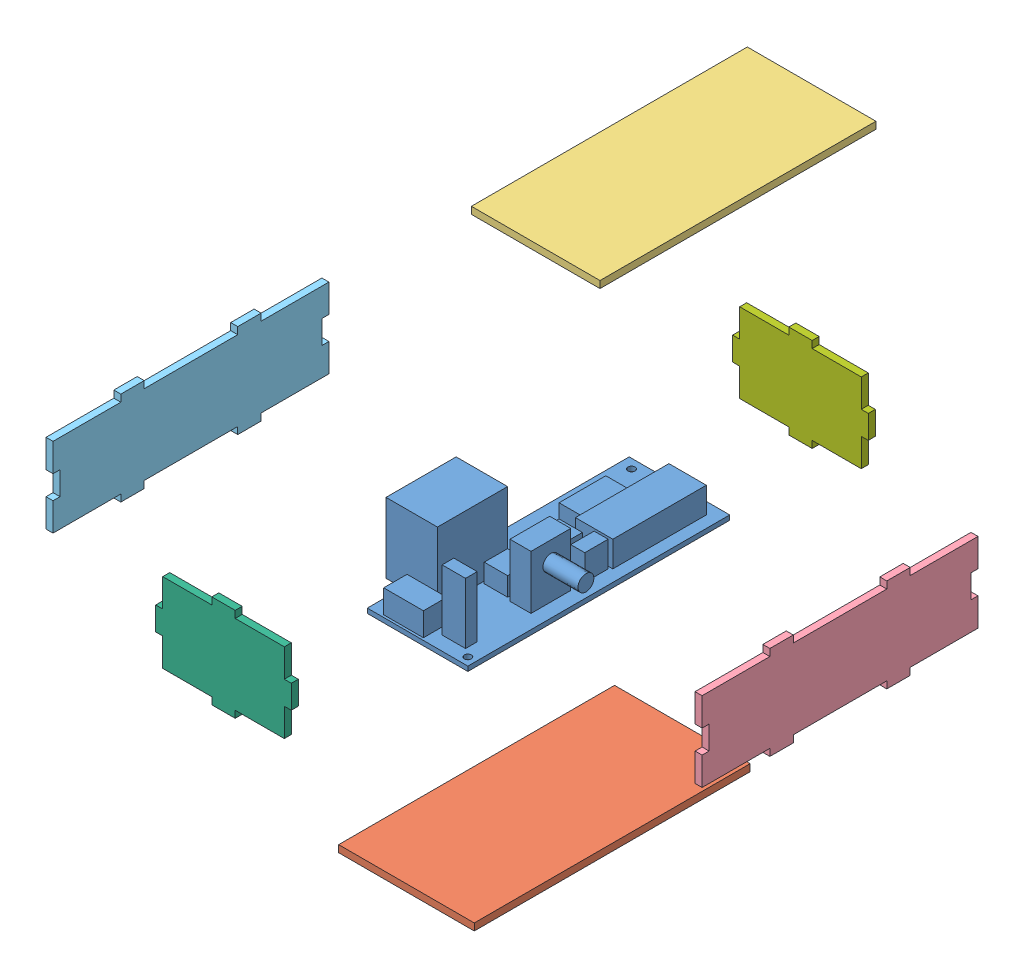
SolidWorks assembly Assem1, configuration Default. Lengths in mm.
Overall size (190.05 127.77 267.42).
7 component instances, 7 part files, 0 mates.
Components (placement in the parent):
- Board-1: Board [Default] at (38.8628 52.2316 80.3483) size (59 32 112)
- Part1-1: Part1 [Default] at (95.8183 19.1955 139.0641) size (58 3 118)
- Part1 - Copy-1: Part1 - Copy [Default] at (6.8607 139.7799 -5.1669) size (55 3 118)
- Part2-1: Part2 [Default] at (133.912 52.7354 53.7256) size (3 40 118)
- Part2 - Copy-1: Part2 - Copy [Default] at (-53.1424 98.6764 144.254) size (3 40 118)
- Part3-1: Part3 [Default] at (-14.2534 35.0122 163.2303) size (58 40 3)
- Part3 - Copy-1: Part3 - Copy [Default] at (69.3599 95.2012 0.1013) size (58 40 3)
